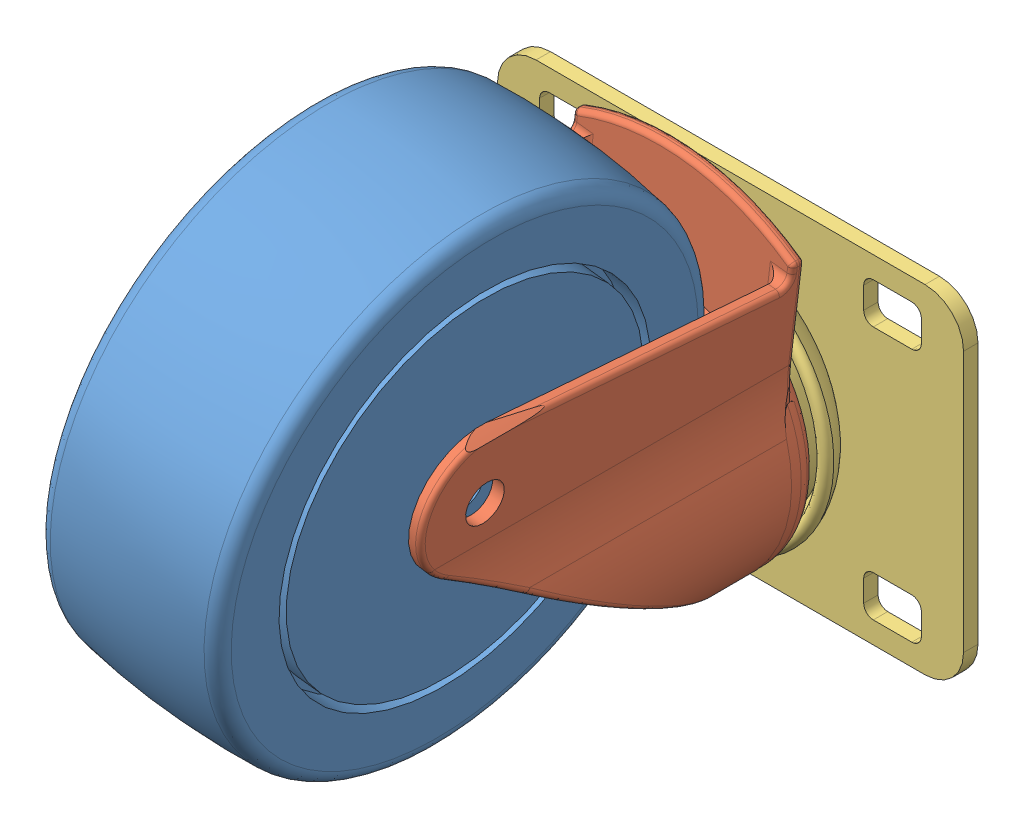
SolidWorks assembly CasterWheel, configuration Default. Lengths in mm.
Overall size (96.8 124.28 137.46).
3 component instances, 3 part files, 5 mates.
Components (placement in the parent):
- wheel-1: wheel [Default] at (-52.6478 31.0459 -52.0396) x (0.011925 0.098788 0.995037) z (-0.119247 -0.987866 0.099506) size (104.08 37.5 104.08)
- CasterWheelHolder-1: CasterWheelHolder [Default] at (-56.315 0.6665 -132.5396) x (0.992793 -0.119842 0) z (0 0 1) size (55.41 77.14 82.84)
- CasterHolder-1: CasterHolder [Default] at (-56.315 0.6665 -132.5396) size (96.8 70.2 11)
Mates (geometry in assembly coordinates):
- Coincident6: coincident anti-aligned: plane of CasterWheelHolder-1 through (-56.315 0.6665 -121.5396) normal (0 0 -1); plane of CasterHolder-1 through (-56.315 0.6665 -121.5396) normal (0 0 1)
- Concentric3: concentric aligned: cylinder of CasterWheelHolder-1 through (-56.315 0.6665 -111.5396) axis (0 0 -1) radius 23; cylinder of CasterHolder-1 through (-56.315 0.6665 -111.5396) axis (0 0 -1) radius 23
- Concentric4: concentric aligned: cylinder of wheel-1 through (64.75 16.8746 -52.0396) axis (-0.992793 0.119842 0) radius 4; cylinder of CasterWheelHolder-1 through (0.963 24.5745 -52.0396) axis (-0.992793 0.119842 0) radius 4
- Coincident12: coincident anti-aligned: plane of wheel-1 through (-52.6478 31.0459 -52.0396) normal (-0.992793 0.119842 0); plane of CasterWheelHolder-1 through (-56.315 0.6665 -132.5396) normal (0.992793 -0.119842 0)
- Tangent3: tangent: torus of wheel-1; plane of assembly through (0 0 0) normal (0 0 1)
